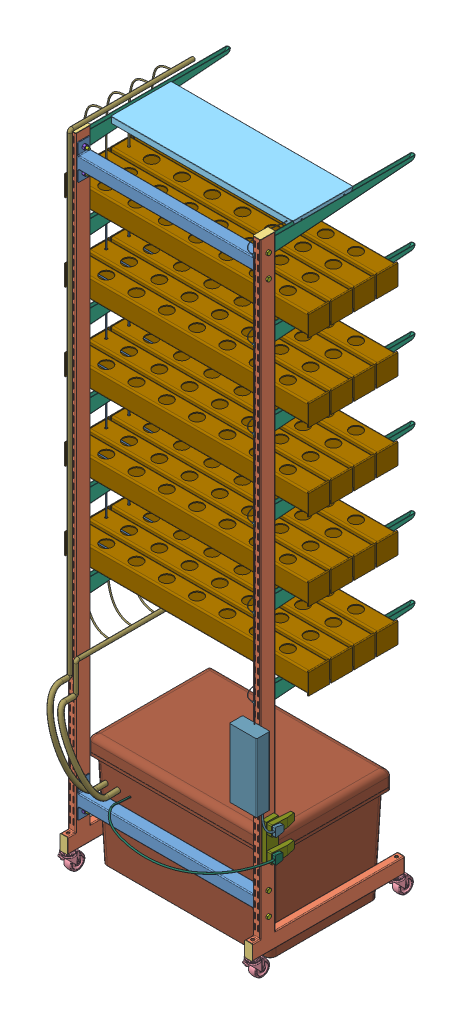
SolidWorks assembly C-L-600, configuration Default. Lengths in mm.
Overall size (806 2127.7 608.88).
90 component instances, 16 part files, 242 mates.
Components (placement in the parent):
- TB-600-1: TB-600 [Default] at (0 2029.5 0) size (585 115 40)
- TB-600-2: TB-600 [Default] at (0 205.5 0) size (585 115 40)
- TSU-F-L-P-1: TSU-F-L-P [Default] at (305 113.5 -25) size (25 2050 500)
- TSU-F-L-P-2: TSU-F-L-P [Default] at (-305 113.5 -25) size (25 2050 500)
- TSU-CAP-1: TSU-CAP [Default] at (-305.1 113.6 -39.9) x (-1 0 0) z (0 0 -1) size (25.2 50.2 6.5)
- TSU-CAP-2: TSU-CAP [Default] at (304.9 113.6 -39.9) x (-1 0 0) z (0 0 -1) size (25.2 50.2 6.5)
- TSU-CAP-3: TSU-CAP [Default] at (305.1 1703.4 -25.1) x (1 0 0) z (0 1 0) size (25.2 50.2 6.5)
- TSU-CAP-4: TSU-CAP [Default] at (304.9 113.6 -360.1) size (25.2 50.2 6.5)
- TSU-CAP-5: TSU-CAP [Default] at (-304.9 1703.4 -25.1) x (1 0 0) z (0 1 0) size (25.2 50.2 6.5)
- TSU-CAP-6: TSU-CAP [Default] at (-304.9 113.6 -360.1) size (25.2 50.2 6.5)
- 2834T320_THREADED-STEM SWIVEL CASTER-1: 2834T320_THREADED-STEM SWIVEL CASTER [2834T32] at (305 82.55 -437.5) x (0 0 -1) z (1 0 0) size (67.73 101.87 56.07)
- 2834T320_THREADED-STEM SWIVEL CASTER-2: 2834T320_THREADED-STEM SWIVEL CASTER [2834T32] at (-305 82.55 37.5) x (0 0 -1) z (1 0 0) size (67.73 101.87 56.07)
- 2834T320_THREADED-STEM SWIVEL CASTER-3: 2834T320_THREADED-STEM SWIVEL CASTER [2834T32] at (305 82.55 37.5) x (0 0 -1) z (1 0 0) size (67.73 101.87 56.07)
- 2834T320_THREADED-STEM SWIVEL CASTER-4: 2834T320_THREADED-STEM SWIVEL CASTER [2834T32] at (-305 82.55 -437.5) x (0 0 -1) z (1 0 0) size (67.73 101.87 56.07)
- TSS-600-1: TSS-600 [Default] at (0 818 -198.7822) size (607 37.13 331.17)
- TSUB-1: TSUB [Default] at (305 766.5 -25) x (-1 0 0) z (0 0 -1) size (14.07 50.86 484.03)
- TSUB-2: TSUB [Default] at (-305 766.5 -25) x (-1 0 0) z (0 0 -1) size (14.07 50.86 484.03)
- TSUB-3: TSUB [Default] at (-305 1022.5 -25) x (-1 0 0) z (0 0 -1) size (14.07 50.86 484.03)
- TSUB-4: TSUB [Default] at (305 1022.5 -25) x (-1 0 0) z (0 0 -1) size (14.07 50.86 484.03)
- TSS-600-2: TSS-600 [Default] at (0 1074 -198.7822) size (607 37.13 331.17)
- TSUB-5: TSUB [Default] at (-305 1534.5 -25) x (-1 0 0) z (0 0 -1) size (14.07 50.86 484.03)
- TSUB-6: TSUB [Default] at (305 1534.5 -25) x (-1 0 0) z (0 0 -1) size (14.07 50.86 484.03)
- TSS-600-3: TSS-600 [Default] at (0 1586 -198.7822) size (607 37.13 331.17)
- TSUB-7: TSUB [Default] at (-305 2046.5 -25) x (-1 0 0) z (0 0 -1) size (14.07 50.86 484.03)
- TSUB-8: TSUB [Default] at (305 2046.5 -25) x (-1 0 0) z (0 0 -1) size (14.07 50.86 484.03)
- TSS-600-4: TSS-600 [Default] at (0 2098 -198.7822) size (607 37.13 331.17)
- TSUB-9: TSUB [Default] at (-305 1278.5 -25) x (-1 0 0) z (0 0 -1) size (14.07 50.86 484.03)
- TSUB-10: TSUB [Default] at (305 1278.5 -25) x (-1 0 0) z (0 0 -1) size (14.07 50.86 484.03)
- TSS-600-5: TSS-600 [Default] at (0 1330 -198.7822) size (607 37.13 331.17)
- TSUB-11: TSUB [Default] at (-305 1790.5 -25) x (-1 0 0) z (0 0 -1) size (14.07 50.86 484.03)
- TSUB-12: TSUB [Default] at (305 1790.5 -25) x (-1 0 0) z (0 0 -1) size (14.07 50.86 484.03)
- TSS-600-6: TSS-600 [Default] at (0 1842 -198.7822) size (607 37.13 331.17)
- hex bolt gradeab2_bsi-10: hex bolt gradeab2_bsi [BS EN 28765 - M8x1 x 45 x 22-N] at (322.8 2067 0) x (-1 0 0) z (0 -0.924225 -0.381849) size (50.3 15.01 13)
- hex bolt gradeab2_bsi-11: hex bolt gradeab2_bsi [BS EN 28765 - M8x1 x 45 x 22-N] at (322.8 1992 0) x (-1 0 0) z (0 -0.999974 0.007224) size (50.3 15.01 13)
- hex bolt gradeab2_bsi-12: hex bolt gradeab2_bsi [BS EN 28765 - M8x1 x 45 x 22-N] at (-322.8 2067 0) size (50.3 15.01 13)
- hex bolt gradeab2_bsi-13: hex bolt gradeab2_bsi [BS EN 28765 - M8x1 x 45 x 22-N] at (-322.8 1992 0) size (50.3 15.01 13)
- hex bolt gradeab2_bsi-14: hex bolt gradeab2_bsi [BS EN 28765 - M8x1 x 45 x 22-N] at (-322.8 168 0) size (50.3 15.01 13)
- hex bolt gradeab2_bsi-15: hex bolt gradeab2_bsi [BS EN 28765 - M8x1 x 45 x 22-N] at (-322.8 243 0) size (50.3 15.01 13)
- hex bolt gradeab2_bsi-16: hex bolt gradeab2_bsi [BS EN 28765 - M8x1 x 45 x 22-N] at (322.8 168 0) x (-1 0 0) z (0 0.924225 0.381849) size (50.3 15.01 13)
- hex bolt gradeab2_bsi-17: hex bolt gradeab2_bsi [BS EN 28765 - M8x1 x 45 x 22-N] at (322.8 243 0) x (-1 0 0) z (0 -0.924225 -0.381849) size (50.3 15.01 13)
- hex nut gradec_bsi-1: hex nut gradec_bsi [BS EN 24034 - M8 - N] at (281.6 2067 0) x (0 0 1) z (-1 0 0) size (13 15.01 7.9)
- hex nut gradec_bsi-2: hex nut gradec_bsi [BS EN 24034 - M8 - N] at (281.6 1992 0) x (0 0 1) z (-1 0 0) size (13 15.01 7.9)
- hex nut gradec_bsi-3: hex nut gradec_bsi [BS EN 24034 - M8 - N] at (-281.6 2067 0) x (0 0 -1) z (1 0 0) size (13 15.01 7.9)
- hex nut gradec_bsi-4: hex nut gradec_bsi [BS EN 24034 - M8 - N] at (-281.6 1992 0) x (0 0.383049 0.923728) z (1 0 0) size (13 15.01 7.9)
- hex nut gradec_bsi-5: hex nut gradec_bsi [BS EN 24034 - M8 - N] at (-281.6 243 0) x (0 0 -1) z (1 0 0) size (13 15.01 7.9)
- hex nut gradec_bsi-6: hex nut gradec_bsi [BS EN 24034 - M8 - N] at (281.6 243 0) x (0 0 1) z (-1 0 0) size (13 15.01 7.9)
- hex nut gradec_bsi-7: hex nut gradec_bsi [BS EN 24034 - M8 - N] at (281.6 168 0) x (0 0 1) z (-1 0 0) size (13 15.01 7.9)
- hex nut gradec_bsi-8: hex nut gradec_bsi [BS EN 24034 - M8 - N] at (-281.6 168 0) x (0 0 -1) z (1 0 0) size (13 15.01 7.9)
- GB-600-b-1: GB-600-b [Default] at (0 1106.5 -233.7344) size (806 70 70)
- GB-600-p-1: GB-600-p [Default] at (0 1106.5 -233.7344) size (92 218.31 4)
- GB-600-p-2: GB-600-p [Default] at (0 1106.5 -308.7344) size (92 218.31 4)
- GB-600-b-2: GB-600-b [Default] at (0 1106.5 -308.7344) size (806 70 70)
- GB-600-p-3: GB-600-p [Default] at (0 1106.5 -83.7344) size (92 218.31 4)
- GB-600-b-3: GB-600-b [Default] at (0 1106.5 -83.7344) size (806 70 70)
- GB-600-p-4: GB-600-p [Default] at (0 1106.5 -158.7344) size (92 218.31 4)
- GB-600-b-4: GB-600-b [Default] at (0 1106.5 -158.7344) size (806 70 70)
- GB-600-b-5: GB-600-b [Default] at (0 850.5 -83.7344) size (806 70 70)
- GB-600-b-6: GB-600-b [Default] at (0 850.5 -158.7344) size (806 70 70)
- GB-600-b-7: GB-600-b [Default] at (0 850.5 -233.7344) size (806 70 70)
- GB-600-b-8: GB-600-b [Default] at (0 850.5 -308.7344) size (806 70 70)
- GB-600-b-9: GB-600-b [Default] at (0 1618.5 -83.7344) size (806 70 70)
- GB-600-b-10: GB-600-b [Default] at (0 1618.5 -158.7344) size (806 70 70)
- GB-600-b-11: GB-600-b [Default] at (0 1618.5 -233.7344) size (806 70 70)
- GB-600-b-12: GB-600-b [Default] at (0 1618.5 -308.7344) size (806 70 70)
- GB-600-p-5: GB-600-p [Default] at (0 1618.5 -83.7344) size (92 218.31 4)
- GB-600-p-6: GB-600-p [Default] at (0 1618.5 -158.7344) size (92 218.31 4)
- GB-600-p-7: GB-600-p [Default] at (0 1618.5 -233.7344) size (92 218.31 4)
- GB-600-p-8: GB-600-p [Default] at (0 1618.5 -308.7344) size (92 218.31 4)
- GB-600-p-9: GB-600-p [Default] at (0 1362.5 -308.7344) size (92 218.31 4)
- GB-600-p-10: GB-600-p [Default] at (0 1362.5 -233.7344) size (92 218.31 4)
- GB-600-p-11: GB-600-p [Default] at (0 1362.5 -158.7344) size (92 218.31 4)
- GB-600-p-12: GB-600-p [Default] at (0 1362.5 -83.7344) size (92 218.31 4)
- GB-600-b-13: GB-600-b [Default] at (0 1362.5 -308.7344) size (806 70 70)
- GB-600-b-14: GB-600-b [Default] at (0 1362.5 -233.7344) size (806 70 70)
- GB-600-b-15: GB-600-b [Default] at (0 1362.5 -158.7344) size (806 70 70)
- GB-600-b-16: GB-600-b [Default] at (0 1362.5 -83.7344) size (806 70 70)
- GB-600-p-13: GB-600-p [Default] at (0 1874.5 -308.7344) size (92 218.31 4)
- GB-600-p-14: GB-600-p [Default] at (0 1874.5 -233.7344) size (92 218.31 4)
- GB-600-p-15: GB-600-p [Default] at (0 1874.5 -158.7344) size (92 218.31 4)
- GB-600-p-16: GB-600-p [Default] at (0 1874.5 -83.7344) size (92 218.31 4)
- GB-600-b-17: GB-600-b [Default] at (0 1874.5 -83.7344) size (806 70 70)
- GB-600-b-18: GB-600-b [Default] at (0 1874.5 -158.7344) size (806 70 70)
- GB-600-b-19: GB-600-b [Default] at (0 1874.5 -233.7344) size (806 70 70)
- GB-600-b-20: GB-600-b [Default] at (0 1874.5 -308.7344) size (806 70 70)
- WT-1: WT [Default] at (0 320 -225) size (600 370 400)
- Plumbing-1: Plumbing [Default] at (-305 113.5 25) size (241.4 2067.5 489.85)
- Wire-1: Wire [Default] at (0 2060.8692 -198.7822) x (-1 0 0) z (0 -1 0) size (2 2 1357)
- CCD-1: CCD [Default] at (305 113.5 -25) x (0 0 -1) z (1 0 0) size (82.56 307.09 97.63)
- Pump-1: Pump [Default] at (0 5 -225) x (1 0 0) z (0 1 0) size (624.24 196.22 364.08)
- Power Bar-1: Power Bar [Default] at (317.5 113.5 -25) x (0 0 -1) z (1 0 0) size (82.62 120 30)
Mates (geometry in assembly coordinates):
- Coincident5: coincident aligned: plane of TB-600-2 through (0 205.5 0) normal (1 0 0)
- Coincident6: coincident aligned: plane of TB-600-2 through (0 205.5 0) normal (0 0 1)
- Tangent1: tangent anti-aligned: torus of 2834T320_THREADED-STEM SWIVEL CASTER-1
- Concentric5: concentric anti-aligned: cylinder of TSU-F-L-P-1 through (305 113.5 -437.5) axis (0 -1 0) radius 5.1; cylinder of 2834T320_THREADED-STEM SWIVEL CASTER-1 through (305 101.6 -437.5) axis (0 1 0) radius 4.7625
- Coincident7: coincident anti-aligned: plane of TB-600-2 through (292.5 205.5 0) normal (1 0 0); plane of TSU-F-L-P-1 through (292.5 2113.5 -22) normal (-1 0 0)
- Concentric6: concentric anti-aligned: cylinder of TB-600-2 through (292.5 243 0) axis (-1 0 0) radius 4.5; cylinder of TSU-F-L-P-1 through (290.9 243 0) axis (1 0 0) radius 4.5
- Coincident8: coincident anti-aligned: plane of TSU-F-L-P-1 through (305 63.5 -450) normal (0 -1 0); plane of 2834T320_THREADED-STEM SWIVEL CASTER-1 through (305 63.5 -421.3957) normal (0 1 0)
- Concentric7: concentric anti-aligned: cylinder of TB-600-1 through (292.5 2067 0) axis (-1 0 0) radius 4.5; cylinder of TSU-F-L-P-1 through (292.5 2067 0) axis (1 0 0) radius 4.5
- Coincident9: coincident anti-aligned: plane of TB-600-1 through (292.5 2029.5 0) normal (1 0 0); plane of TSU-F-L-P-1 through (292.5 2113.5 -22) normal (-1 0 0)
- Concentric8: concentric aligned: cylinder of TB-600-2 through (-292.5 168 0) axis (1 0 0) radius 4.5; cylinder of TSU-F-L-P-2 through (-319.1 168 0) axis (1 0 0) radius 4.5
- Coincident10: coincident anti-aligned: plane of TB-600-2 through (-292.5 205.5 0) normal (-1 0 0); plane of TSU-F-L-P-2 through (-292.5 2113.5 -22) normal (1 0 0)
- Concentric9: concentric anti-aligned: cylinder of TSU-F-L-P-2 through (-305 113.5 -437.5) axis (0 -1 0) radius 5.1; cylinder of 2834T320_THREADED-STEM SWIVEL CASTER-4 through (-305 101.6 -437.5) axis (0 1 0) radius 4.7625
- Concentric10: concentric aligned: cylinder of TB-600-1 through (-292.5 1992 0) axis (1 0 0) radius 4.5; cylinder of TSU-F-L-P-2 through (-317.5 1992 0) axis (1 0 0) radius 4.5
- Concentric11: concentric aligned: cylinder of TB-600-1 through (-292.5 2067 0) axis (1 0 0) radius 4.5; cylinder of TSU-F-L-P-2 through (-317.5 2067 0) axis (1 0 0) radius 4.5
- Parallel4: parallel aligned: plane of TSU-F-L-P-1 through (317.5 2113.5 -22) normal (1 0 0); plane of 2834T320_THREADED-STEM SWIVEL CASTER-1 through (316.9062 47.2916 -458.1375) normal (1 0 0)
- Coincident16: coincident anti-aligned: plane of TSU-F-L-P-2 through (-305 63.5 -450) normal (0 -1 0); plane of 2834T320_THREADED-STEM SWIVEL CASTER-4 through (-305 63.5 -421.3957) normal (0 1 0)
- Concentric12: concentric anti-aligned: cylinder of TSU-F-L-P-1 through (305 113.5 37.5) axis (0 -1 0) radius 5.1; cylinder of 2834T320_THREADED-STEM SWIVEL CASTER-3 through (305 101.6 37.5) axis (0 1 0) radius 4.7625
- Coincident17: coincident anti-aligned: plane of TSU-F-L-P-1 through (305 63.5 -450) normal (0 -1 0); plane of 2834T320_THREADED-STEM SWIVEL CASTER-3 through (305 63.5 53.6043) normal (0 1 0)
- Coincident18: coincident aligned: plane of 2834T320_THREADED-STEM SWIVEL CASTER-1 through (316.9062 47.2916 -458.1375) normal (1 0 0); plane of 2834T320_THREADED-STEM SWIVEL CASTER-3 through (316.9062 47.2916 16.8625) normal (1 0 0)
- Concentric13: concentric anti-aligned: cylinder of TSU-F-L-P-2 through (-305 113.5 37.5) axis (0 -1 0) radius 5.1; cylinder of 2834T320_THREADED-STEM SWIVEL CASTER-2 through (-305 101.6 37.5) axis (0 1 0) radius 4.7625
- Coincident19: coincident anti-aligned: plane of TSU-F-L-P-2 through (-305 63.5 -450) normal (0 -1 0); plane of 2834T320_THREADED-STEM SWIVEL CASTER-2 through (-305 63.5 53.6043) normal (0 1 0)
- Parallel6: parallel aligned: plane of TSU-F-L-P-2 through (-317.5 2113.5 -22) normal (-1 0 0); plane of 2834T320_THREADED-STEM SWIVEL CASTER-2 through (-316.9062 47.2916 16.8625) normal (-1 0 0)
- Coincident21: coincident anti-aligned: plane of TSU-F-L-P-1 through (294 2113.5 0) normal (1 0 0); plane of TSU-CAP-4 through (294 113.6 45) normal (-1 0 0)
- Coincident22: coincident anti-aligned: plane of TSU-F-L-P-1 through (314.5 112 -450) normal (0 -1 0); plane of TSU-CAP-4 through (304.9 112 45) normal (0 1 0)
- Coincident23: coincident anti-aligned: plane of TSU-F-L-P-1 through (314.5 110.5 50) normal (0 0 1); plane of TSU-CAP-4 through (304.9 113.6 50) normal (0 0 -1)
- Coincident24: coincident anti-aligned: plane of TSU-F-L-P-2 through (-294 2113.5 0) normal (-1 0 0); plane of TSU-CAP-6 through (-294 113.6 45) normal (1 0 0)
- Coincident25: coincident anti-aligned: plane of TSU-F-L-P-2 through (-295.5 112 -450) normal (0 -1 0); plane of TSU-CAP-6 through (-304.9 112 45) normal (0 1 0)
- Coincident26: coincident anti-aligned: plane of TSU-F-L-P-2 through (-295.5 110.5 50) normal (0 0 1); plane of TSU-CAP-6 through (-304.9 113.6 50) normal (0 0 -1)
- Coincident27: coincident anti-aligned: plane of TSU-F-L-P-1 through (294 2113.5 0) normal (1 0 0); plane of TSU-CAP-2 through (294 113.6 -445) normal (-1 0 0)
- Coincident28: coincident anti-aligned: plane of TSU-F-L-P-1 through (314.5 112 -450) normal (0 -1 0); plane of TSU-CAP-2 through (304.9 112 -445) normal (0 1 0)
- Coincident29: coincident anti-aligned: plane of TSU-F-L-P-1 through (314.5 110.5 -450) normal (0 0 -1); plane of TSU-CAP-2 through (304.9 113.6 -450) normal (0 0 1)
- Coincident30: coincident anti-aligned: plane of TSU-F-L-P-2 through (-316 2113.5 0) normal (1 0 0); plane of TSU-CAP-1 through (-316 113.6 -445) normal (-1 0 0)
- Coincident31: coincident anti-aligned: plane of TSU-F-L-P-2 through (-295.5 112 -450) normal (0 -1 0); plane of TSU-CAP-1 through (-305.1 112 -445) normal (0 1 0)
- Coincident32: coincident anti-aligned: plane of TSU-F-L-P-2 through (-295.5 110.5 -450) normal (0 0 -1); plane of TSU-CAP-1 through (-305.1 113.6 -450) normal (0 0 1)
- Coincident33: coincident anti-aligned: plane of TSU-F-L-P-1 through (316 2113.5 0) normal (-1 0 0); plane of TSU-CAP-3 through (316 2108.5 -25.1) normal (1 0 0)
- Coincident34: coincident anti-aligned: plane of TSU-F-L-P-1 through (314.5 2113.5 -23.5) normal (0 0 1); plane of TSU-CAP-3 through (305.1 2108.5 -23.5) normal (0 0 -1)
- Coincident35: coincident anti-aligned: plane of TSU-F-L-P-1 through (314.5 2113.5 -22) normal (0 1 0); plane of TSU-CAP-3 through (305.1 2113.5 -25.1) normal (0 -1 0)
- Coincident36: coincident anti-aligned: plane of TSU-F-L-P-2 through (-294 2113.5 0) normal (-1 0 0); plane of TSU-CAP-5 through (-294 2108.5 -25.1) normal (1 0 0)
- Coincident37: coincident anti-aligned: plane of TSU-F-L-P-2 through (-295.5 2113.5 -23.5) normal (0 0 1); plane of TSU-CAP-5 through (-304.9 2108.5 -23.5) normal (0 0 -1)
- Coincident38: coincident anti-aligned: plane of TSU-F-L-P-2 through (-295.5 2113.5 -22) normal (0 1 0); plane of TSU-CAP-5 through (-304.9 2113.5 -25.1) normal (0 -1 0)
- Parallel7: parallel aligned: plane of TSU-F-L-P-2 through (-292.5 2113.5 -22) normal (1 0 0); plane of 2834T320_THREADED-STEM SWIVEL CASTER-4 through (-293.0938 47.2916 -458.1375) normal (1 0 0)
- Coincident41: coincident anti-aligned: plane of TSU-F-L-P-1 through (298 273.5 0.001) normal (1 0 0); plane of TSUB-1 through (298 766.5 -25) normal (-1 0 0)
- Coincident42: coincident anti-aligned: plane of TSU-F-L-P-1 through (305 2113.5 -25) normal (0 0 -1); plane of TSUB-1 through (312 766.5 -25) normal (0 0 1)
- Parallel8: parallel: line of TSU-F-L-P-1 through (309 342 -23.5) axis (0 0 -1); plane of TSUB-1 through (298 816.5 -25) normal (0 1 0)
- Coincident44: coincident anti-aligned: plane of TSS-600-1 through (299.5 798 -198.7822) normal (-1 0 0); plane of TSUB-1 through (299.5 766.5 -25) normal (1 0 0)
- Coincident45: coincident anti-aligned: plane of TSS-600-1 through (301 816.5 -100.2822) normal (0 -1 0); plane of TSUB-1 through (298 816.5 -25) normal (0 1 0)
- Coincident46: coincident anti-aligned: plane of TSU-F-L-P-2 through (-312 369.5 0.001) normal (1 0 0); plane of TSUB-2 through (-312 766.5 -25) normal (-1 0 0)
- Coincident47: coincident anti-aligned: plane of TSU-F-L-P-2 through (-305 2113.5 -25) normal (0 0 -1); plane of TSUB-2 through (-312 766.5 -25) normal (0 0 1)
- Coincident48: coincident anti-aligned: plane of TSS-600-1 through (301 816.5 -100.2822) normal (0 -1 0); plane of TSUB-2 through (-312 816.5 -25) normal (0 1 0)
- Coincident49: coincident anti-aligned: plane of TSU-F-L-P-1 through (312 1041.5 0.001) normal (-1 0 0); plane of TSUB-4 through (312 1022.5 -25) normal (1 0 0)
- Coincident50: coincident anti-aligned: plane of TSU-F-L-P-1 through (305 2113.5 -25) normal (0 0 -1); plane of TSUB-4 through (312 1022.5 -25) normal (0 0 1)
- Coincident51: coincident anti-aligned: plane of TSU-F-L-P-2 through (-298 1073.5 0.001) normal (-1 0 0); plane of TSUB-3 through (-298 1022.5 -25) normal (1 0 0)
- Coincident52: coincident anti-aligned: plane of TSU-F-L-P-2 through (-305 2113.5 -25) normal (0 0 -1); plane of TSUB-3 through (-312 1022.5 -25) normal (0 0 1)
- Coincident53: coincident anti-aligned: plane of TSUB-4 through (298 1072.5 -25) normal (0 1 0); plane of TSS-600-2 through (301 1072.5 -100.2822) normal (0 -1 0)
- Coincident54: coincident anti-aligned: plane of TSUB-3 through (-312 1072.5 -25) normal (0 1 0); plane of TSS-600-2 through (301 1072.5 -100.2822) normal (0 -1 0)
- Coincident55: coincident anti-aligned: plane of TSUB-4 through (299.5 1022.5 -25) normal (1 0 0); plane of TSS-600-2 through (299.5 1054 -198.7822) normal (-1 0 0)
- Coincident56: coincident anti-aligned: plane of TSUB-6 through (299.5 1534.5 -25) normal (1 0 0); plane of TSS-600-3 through (299.5 1566 -198.7822) normal (-1 0 0)
- Coincident57: coincident anti-aligned: plane of TSUB-6 through (298 1584.5 -25) normal (0 1 0); plane of TSS-600-3 through (301 1584.5 -100.2822) normal (0 -1 0)
- Coincident58: coincident anti-aligned: plane of TSUB-5 through (-312 1584.5 -25) normal (0 1 0); plane of TSS-600-3 through (301 1584.5 -100.2822) normal (0 -1 0)
- Coincident59: coincident anti-aligned: plane of TSUB-8 through (299.5 2046.5 -25) normal (1 0 0); plane of TSS-600-4 through (299.5 2078 -198.7822) normal (-1 0 0)
- Coincident60: coincident anti-aligned: plane of TSUB-8 through (298 2096.5 -25) normal (0 1 0); plane of TSS-600-4 through (301 2096.5 -100.2822) normal (0 -1 0)
- Coincident61: coincident anti-aligned: plane of TSUB-7 through (-312 2096.5 -25) normal (0 1 0); plane of TSS-600-4 through (301 2096.5 -100.2822) normal (0 -1 0)
- Coincident62: coincident anti-aligned: plane of TSUB-10 through (299.5 1278.5 -25) normal (1 0 0); plane of TSS-600-5 through (299.5 1310 -198.7822) normal (-1 0 0)
- Coincident63: coincident anti-aligned: plane of TSUB-10 through (298 1328.5 -25) normal (0 1 0); plane of TSS-600-5 through (301 1328.5 -100.2822) normal (0 -1 0)
- Coincident64: coincident anti-aligned: plane of TSUB-9 through (-312 1328.5 -25) normal (0 1 0); plane of TSS-600-5 through (301 1328.5 -100.2822) normal (0 -1 0)
- Coincident65: coincident anti-aligned: plane of TSUB-12 through (299.5 1790.5 -25) normal (1 0 0); plane of TSS-600-6 through (299.5 1822 -198.7822) normal (-1 0 0)
- Coincident66: coincident anti-aligned: plane of TSUB-12 through (298 1840.5 -25) normal (0 1 0); plane of TSS-600-6 through (301 1840.5 -100.2822) normal (0 -1 0)
- Coincident67: coincident anti-aligned: plane of TSUB-11 through (-312 1840.5 -25) normal (0 1 0); plane of TSS-600-6 through (301 1840.5 -100.2822) normal (0 -1 0)
- Coincident70: coincident anti-aligned: plane of TSU-F-L-P-1 through (305 2113.5 -25) normal (0 0 -1); plane of TSUB-10 through (298 1278.5 -25) normal (0 0 1)
- Coincident71: coincident anti-aligned: plane of TSU-F-L-P-2 through (-305 2113.5 -25) normal (0 0 -1); plane of TSUB-9 through (-312 1278.5 -25) normal (0 0 1)
- Coincident72: coincident aligned: plane of TSUB-3 through (-298 1022.5 -25) normal (1 0 0); plane of TSUB-9 through (-298 1278.5 -25) normal (1 0 0)
- Coincident73: coincident aligned: plane of TSUB-4 through (298 1022.5 -25) normal (-1 0 0); plane of TSUB-10 through (298 1278.5 -25) normal (-1 0 0)
- Coincident74: coincident anti-aligned: plane of TSU-F-L-P-1 through (305 2113.5 -25) normal (0 0 -1); plane of TSUB-6 through (298 1534.5 -25) normal (0 0 1)
- Coincident75: coincident anti-aligned: plane of TSU-F-L-P-2 through (-305 2113.5 -25) normal (0 0 -1); plane of TSUB-5 through (-312 1534.5 -25) normal (0 0 1)
- Coincident76: coincident aligned: plane of TSUB-5 through (-298 1534.5 -25) normal (1 0 0); plane of TSUB-9 through (-298 1278.5 -25) normal (1 0 0)
- Coincident78: coincident aligned: plane of TSUB-6 through (312 1534.5 -25) normal (1 0 0); plane of TSUB-12 through (312 1790.5 -25) normal (1 0 0)
- Coincident79: coincident aligned: plane of TSUB-6 through (298 1534.5 -25) normal (-1 0 0); plane of TSUB-10 through (298 1278.5 -25) normal (-1 0 0)
- Coincident80: coincident anti-aligned: plane of TSU-F-L-P-1 through (305 2113.5 -25) normal (0 0 -1); plane of TSUB-12 through (298 1790.5 -25) normal (0 0 1)
- Coincident81: coincident anti-aligned: plane of TSU-F-L-P-2 through (-312 1873.5 0.001) normal (1 0 0); plane of TSUB-11 through (-312 1790.5 -25) normal (-1 0 0)
- Coincident82: coincident anti-aligned: plane of TSU-F-L-P-2 through (-305 2113.5 -25) normal (0 0 -1); plane of TSUB-11 through (-312 1790.5 -25) normal (0 0 1)
- Coincident83: coincident anti-aligned: plane of TSU-F-L-P-2 through (-312 1969.5 0.001) normal (1 0 0); plane of TSUB-7 through (-312 2046.5 -25) normal (-1 0 0)
- Coincident84: coincident anti-aligned: plane of TSU-F-L-P-2 through (-305 2113.5 -25) normal (0 0 -1); plane of TSUB-7 through (-312 2046.5 -25) normal (0 0 1)
- Coincident85: coincident anti-aligned: plane of TSU-F-L-P-1 through (298 2001.5 0.001) normal (1 0 0); plane of TSUB-8 through (298 2046.5 -25) normal (-1 0 0)
- Coincident86: coincident anti-aligned: plane of TSU-F-L-P-1 through (305 2113.5 -25) normal (0 0 -1); plane of TSUB-8 through (298 2046.5 -25) normal (0 0 1)
- Coincident89: coincident: line of TSU-F-L-P-1 through (309 2070 -23.5) axis (0 0 -1); plane of TSUB-8 through (333.2603 2070 -25) normal (0 1 0)
- Coincident90: coincident aligned: plane of TSS-600-4 through (301 2098 -298.7822) normal (0 0 -1); plane of TSS-600-6 through (301 1842 -298.7822) normal (0 0 -1)
- Coincident91: coincident aligned: plane of TSS-600-3 through (301 1586 -298.7822) normal (0 0 -1); plane of TSS-600-6 through (301 1842 -298.7822) normal (0 0 -1)
- Coincident93: coincident aligned: plane of TSS-600-3 through (301 1586 -298.7822) normal (0 0 -1); plane of TSS-600-5 through (301 1330 -298.7822) normal (0 0 -1)
- Coincident94: coincident aligned: plane of TSS-600-2 through (301 1074 -298.7822) normal (0 0 -1); plane of TSS-600-5 through (301 1330 -298.7822) normal (0 0 -1)
- Coincident95: coincident aligned: plane of TSS-600-1 through (301 818 -298.7822) normal (0 0 -1); plane of TSS-600-2 through (301 1074 -298.7822) normal (0 0 -1)
- Coincident153: coincident: line of TSU-F-L-P-1 through (312 1814 -23.5) axis (0 0 -1); plane of TSUB-12 through (333.2603 1814 -25) normal (0 1 0)
- Coincident155: coincident: line of TSU-F-L-P-1 through (312 1558 -23.5) axis (0 0 -1); plane of TSUB-6 through (333.2603 1558 -25) normal (0 1 0)
- Coincident157: coincident: line of TSU-F-L-P-1 through (312 1302 -23.5) axis (0 0 -1); plane of TSUB-10 through (333.2603 1302 -25) normal (0 1 0)
- Coincident159: coincident: line of TSU-F-L-P-1 through (312 1046 -23.5) axis (0 0 -1); plane of TSUB-4 through (333.2603 1046 -25) normal (0 1 0)
- Coincident167: coincident: line of TSU-F-L-P-1 through (312 790 -23.5) axis (0 0 -1); plane of TSUB-1 through (333.2603 790 -25) normal (0 1 0)
- Concentric15: concentric aligned: cylinder of TSU-F-L-P-1 through (292.5 2067 0) axis (1 0 0) radius 4.5; cylinder of hex bolt gradeab2_bsi-10 through (322.8 2067 0) axis (1 0 0) radius 4
- Coincident181: coincident anti-aligned: plane of TSU-F-L-P-1 through (317.5 2113.5 -22) normal (1 0 0); plane of hex bolt gradeab2_bsi-10 through (317.5 2069.866 -6.9368) normal (-1 0 0)
- Concentric16: concentric aligned: cylinder of TSU-F-L-P-1 through (292.5 1992 0) axis (1 0 0) radius 4.5; cylinder of hex bolt gradeab2_bsi-11 through (322.8 1992 0) axis (1 0 0) radius 4
- Coincident182: coincident anti-aligned: plane of TSU-F-L-P-1 through (317.5 2113.5 -22) normal (1 0 0); plane of hex bolt gradeab2_bsi-11 through (317.5 1991.9458 -7.5054) normal (-1 0 0)
- Concentric17: concentric anti-aligned: cylinder of TB-600-1 through (-292.5 2067 0) axis (1 0 0) radius 4.5; cylinder of hex bolt gradeab2_bsi-12 through (-322.8 2067 0) axis (-1 0 0) radius 4
- Coincident183: coincident anti-aligned: plane of TSU-F-L-P-2 through (-317.5 2113.5 -22) normal (-1 0 0); plane of hex bolt gradeab2_bsi-12 through (-317.5 2074.5056 0) normal (1 0 0)
- Concentric18: concentric anti-aligned: cylinder of TB-600-1 through (-292.5 1992 0) axis (1 0 0) radius 4.5; cylinder of hex bolt gradeab2_bsi-13 through (-322.8 1992 0) axis (-1 0 0) radius 4
- Coincident184: coincident anti-aligned: plane of TSU-F-L-P-2 through (-317.5 2113.5 -22) normal (-1 0 0); plane of hex bolt gradeab2_bsi-13 through (-317.5 1999.5056 0) normal (1 0 0)
- Concentric19: concentric anti-aligned: cylinder of TB-600-2 through (-292.5 243 0) axis (1 0 0) radius 4.5; cylinder of hex bolt gradeab2_bsi-15 through (-322.8 243 0) axis (-1 0 0) radius 4
- Coincident185: coincident anti-aligned: plane of TSU-F-L-P-2 through (-317.5 2113.5 -22) normal (-1 0 0); plane of hex bolt gradeab2_bsi-15 through (-317.5 250.5056 0) normal (1 0 0)
- Concentric20: concentric anti-aligned: cylinder of TB-600-2 through (-292.5 168 0) axis (1 0 0) radius 4.5; cylinder of hex bolt gradeab2_bsi-14 through (-322.8 168 0) axis (-1 0 0) radius 4
- Coincident186: coincident anti-aligned: plane of TSU-F-L-P-2 through (-317.5 2113.5 -22) normal (-1 0 0); plane of hex bolt gradeab2_bsi-14 through (-317.5 175.5056 0) normal (1 0 0)
- Concentric21: concentric anti-aligned: cylinder of TB-600-2 through (292.5 243 0) axis (-1 0 0) radius 4.5; cylinder of hex bolt gradeab2_bsi-17 through (322.8 243 0) axis (1 0 0) radius 4
- Coincident187: coincident anti-aligned: plane of TSU-F-L-P-1 through (317.5 2113.5 -22) normal (1 0 0); plane of hex bolt gradeab2_bsi-17 through (317.5 245.866 -6.9368) normal (-1 0 0)
- Concentric22: concentric aligned: cylinder of TSU-F-L-P-1 through (290.9 168 0) axis (1 0 0) radius 4.5; cylinder of hex bolt gradeab2_bsi-16 through (322.8 168 0) axis (1 0 0) radius 4
- Coincident188: coincident anti-aligned: plane of TSU-F-L-P-1 through (317.5 2113.5 -22) normal (1 0 0); plane of hex bolt gradeab2_bsi-16 through (317.5 165.134 6.9368) normal (-1 0 0)
- Concentric23: concentric anti-aligned: cylinder of hex bolt gradeab2_bsi-10 through (322.8 2067 0) axis (1 0 0) radius 4; cylinder of hex nut gradec_bsi-1 through (289.5 2067 0) axis (-1 0 0) radius 3.4
- Coincident189: coincident anti-aligned: plane of TB-600-1 through (289.5 2029.5 0) normal (-1 0 0); plane of hex nut gradec_bsi-1 through (289.5 2074.5056 0) normal (1 0 0)
- Concentric24: concentric anti-aligned: cylinder of hex bolt gradeab2_bsi-11 through (322.8 1992 0) axis (1 0 0) radius 4; cylinder of hex nut gradec_bsi-2 through (289.5 1992 0) axis (-1 0 0) radius 3.4
- Coincident190: coincident anti-aligned: plane of TB-600-1 through (289.5 2029.5 0) normal (-1 0 0); plane of hex nut gradec_bsi-2 through (289.5 1999.5056 0) normal (1 0 0)
- Concentric25: concentric anti-aligned: cylinder of hex bolt gradeab2_bsi-12 through (-322.8 2067 0) axis (-1 0 0) radius 4; cylinder of hex nut gradec_bsi-3 through (-289.5 2067 0) axis (1 0 0) radius 3.4
- Coincident191: coincident anti-aligned: plane of TB-600-1 through (-289.5 2029.5 0) normal (1 0 0); plane of hex nut gradec_bsi-3 through (-289.5 2074.5056 0) normal (-1 0 0)
- Concentric26: concentric anti-aligned: cylinder of hex bolt gradeab2_bsi-13 through (-322.8 1992 0) axis (-1 0 0) radius 4; cylinder of hex nut gradec_bsi-4 through (-289.5 1992 0) axis (1 0 0) radius 3.4
- Coincident192: coincident anti-aligned: plane of TB-600-1 through (-289.5 2029.5 0) normal (1 0 0); plane of hex nut gradec_bsi-4 through (-289.5 1985.0669 2.875) normal (-1 0 0)
- Concentric27: concentric anti-aligned: cylinder of hex bolt gradeab2_bsi-15 through (-322.8 243 0) axis (-1 0 0) radius 4; cylinder of hex nut gradec_bsi-5 through (-289.5 243 0) axis (1 0 0) radius 3.4
- Coincident193: coincident anti-aligned: plane of TB-600-2 through (-289.5 205.5 0) normal (1 0 0); plane of hex nut gradec_bsi-5 through (-289.5 250.5056 0) normal (-1 0 0)
- Concentric28: concentric anti-aligned: cylinder of hex bolt gradeab2_bsi-14 through (-322.8 168 0) axis (-1 0 0) radius 4; cylinder of hex nut gradec_bsi-8 through (-289.5 168 0) axis (1 0 0) radius 3.4
- Coincident194: coincident anti-aligned: plane of TB-600-2 through (-289.5 205.5 0) normal (1 0 0); plane of hex nut gradec_bsi-8 through (-289.5 175.5056 0) normal (-1 0 0)
- Concentric29: concentric anti-aligned: cylinder of hex bolt gradeab2_bsi-17 through (322.8 243 0) axis (1 0 0) radius 4; cylinder of hex nut gradec_bsi-6 through (289.5 243 0) axis (-1 0 0) radius 3.4
- Concentric30: concentric anti-aligned: cylinder of hex bolt gradeab2_bsi-16 through (322.8 168 0) axis (1 0 0) radius 4; cylinder of hex nut gradec_bsi-7 through (289.5 168 0) axis (-1 0 0) radius 3.4
- Coincident195: coincident anti-aligned: plane of TB-600-2 through (289.5 205.5 0) normal (-1 0 0); plane of hex nut gradec_bsi-6 through (289.5 250.5056 0) normal (1 0 0)
- Coincident196: coincident anti-aligned: plane of TB-600-2 through (289.5 205.5 0) normal (-1 0 0); plane of hex nut gradec_bsi-7 through (289.5 175.5056 0) normal (1 0 0)
- Concentric31: concentric aligned: cylinder of GB-600-b-1 through (-375 1071.5 -233.7344) axis (0 1 0) radius 2; cylinder of GB-600-p-1 through (-375 877 -233.7344) axis (0 1 0) radius 2
- Distance1: distance = 10 mm aligned: plane of GB-600-p-1 through (-375 1087 -233.7344) normal (0 1 0); plane of GB-600-b-1 through (400 1077 -201.2344) normal (0 1 0)
- Parallel10: parallel anti-aligned: plane of TSU-F-L-P-1 through (305 2113.5 -25) normal (0 0 -1); plane of GB-600-b-1 through (400 1074 -201.2344) normal (0 0 1)
- Coincident201: coincident aligned: plane of GB-600-b-1 through (0 1106.5 -233.7344) normal (1 0 0)
- Coincident202: coincident anti-aligned: plane of TSS-600-2 through (301 1074 -98.7822) normal (0 1 0); plane of GB-600-b-1 through (400 1074 -201.2344) normal (0 -1 0)
- Concentric32: concentric aligned: cylinder of GB-600-p-2 through (-375 877 -308.7344) axis (0 1 0) radius 2; cylinder of GB-600-b-2 through (-375 1071.5 -308.7344) axis (0 1 0) radius 2
- Distance2: distance = 10 mm aligned: plane of GB-600-p-2 through (-375 1087 -308.7344) normal (0 1 0); plane of GB-600-b-2 through (400 1077 -276.2344) normal (0 1 0)
- Concentric33: concentric aligned: cylinder of GB-600-p-3 through (-375 877 -83.7344) axis (0 1 0) radius 2; cylinder of GB-600-b-3 through (-375 1071.5 -83.7344) axis (0 1 0) radius 2
- Distance3: distance = 10 mm aligned: plane of GB-600-p-3 through (-375 1087 -83.7344) normal (0 1 0); plane of GB-600-b-3 through (400 1077 -51.2344) normal (0 1 0)
- Concentric34: concentric aligned: cylinder of GB-600-p-4 through (-375 877 -158.7344) axis (0 1 0) radius 2; cylinder of GB-600-b-4 through (-375 1071.5 -158.7344) axis (0 1 0) radius 2
- Distance4: distance = 10 mm aligned: plane of GB-600-p-4 through (-375 1087 -158.7344) normal (0 1 0); plane of GB-600-b-4 through (400 1077 -126.2344) normal (0 1 0)
- Coincident203: coincident anti-aligned: plane of TSS-600-2 through (301 1074 -98.7822) normal (0 1 0); plane of GB-600-b-2 through (400 1074 -276.2344) normal (0 -1 0)
- Coincident204: coincident anti-aligned: plane of TSS-600-2 through (301 1074 -98.7822) normal (0 1 0); plane of GB-600-b-4 through (400 1074 -126.2344) normal (0 -1 0)
- Coincident205: coincident anti-aligned: plane of TSS-600-2 through (301 1074 -98.7822) normal (0 1 0); plane of GB-600-b-3 through (400 1074 -51.2344) normal (0 -1 0)
- Coincident206: coincident aligned: plane of GB-600-b-1 through (403 1106.5 -233.7344) normal (1 0 0); plane of GB-600-b-4 through (403 1106.5 -158.7344) normal (1 0 0)
- Coincident207: coincident aligned: plane of GB-600-b-3 through (403 1106.5 -83.7344) normal (1 0 0); plane of GB-600-b-4 through (403 1106.5 -158.7344) normal (1 0 0)
- Coincident208: coincident aligned: plane of GB-600-b-1 through (403 1106.5 -233.7344) normal (1 0 0); plane of GB-600-b-2 through (403 1106.5 -308.7344) normal (1 0 0)
- Distance5: distance = 10 mm anti-aligned: plane of GB-600-b-4 through (400 1074 -191.2344) normal (0 0 -1); plane of GB-600-b-1 through (400 1074 -201.2344) normal (0 0 1)
- Distance6: distance = 10 mm anti-aligned: plane of GB-600-b-4 through (400 1074 -126.2344) normal (0 0 1); plane of GB-600-b-3 through (400 1074 -116.2344) normal (0 0 -1)
- Distance7: distance = 10 mm anti-aligned: plane of GB-600-b-1 through (400 1074 -266.2344) normal (0 0 -1); plane of GB-600-b-2 through (400 1074 -276.2344) normal (0 0 1)
- Distance8: distance = 10 mm anti-aligned: plane of GB-600-b-6 through (400 818 -126.2344) normal (0 0 1); plane of GB-600-b-5 through (400 818 -116.2344) normal (0 0 -1)
- Distance9: distance = 10 mm anti-aligned: plane of GB-600-b-6 through (400 818 -191.2344) normal (0 0 -1); plane of GB-600-b-7 through (400 818 -201.2344) normal (0 0 1)
- Coincident212: coincident aligned: plane of GB-600-b-5 through (403 850.5 -83.7344) normal (1 0 0); plane of GB-600-b-6 through (403 850.5 -158.7344) normal (1 0 0)
- Coincident213: coincident aligned: plane of GB-600-b-7 through (403 850.5 -233.7344) normal (1 0 0); plane of GB-600-b-8 through (403 850.5 -308.7344) normal (1 0 0)
- Coincident214: coincident aligned: plane of GB-600-b-6 through (403 850.5 -158.7344) normal (1 0 0); plane of GB-600-b-7 through (403 850.5 -233.7344) normal (1 0 0)
- Distance10: distance = 10 mm anti-aligned: plane of GB-600-b-7 through (400 818 -266.2344) normal (0 0 -1); plane of GB-600-b-8 through (400 818 -276.2344) normal (0 0 1)
- Coincident215: coincident aligned: plane of GB-600-b-7 through (400 818 -201.2344) normal (0 -1 0); plane of GB-600-b-8 through (400 818 -276.2344) normal (0 -1 0)
- Coincident216: coincident aligned: plane of GB-600-b-6 through (400 818 -126.2344) normal (0 -1 0); plane of GB-600-b-7 through (400 818 -201.2344) normal (0 -1 0)
- Coincident217: coincident aligned: plane of GB-600-b-5 through (400 818 -51.2344) normal (0 -1 0); plane of GB-600-b-6 through (400 818 -126.2344) normal (0 -1 0)
- Coincident218: coincident anti-aligned: plane of TSS-600-1 through (301 818 -98.7822) normal (0 1 0); plane of GB-600-b-7 through (400 818 -201.2344) normal (0 -1 0)
- Concentric35: concentric aligned: cylinder of GB-600-p-2 through (-375 877 -308.7344) axis (0 1 0) radius 2; cylinder of GB-600-b-8 through (-375 815.499 -308.7344) axis (0 1 0) radius 4
- Concentric36: concentric aligned: cylinder of GB-600-b-9 through (-375 1583.5 -83.7344) axis (0 1 0) radius 2; cylinder of GB-600-p-5 through (-375 1389 -83.7344) axis (0 1 0) radius 2
- Distance11: distance = 10 mm anti-aligned: plane of GB-600-b-10 through (400 1586 -126.2344) normal (0 0 1); plane of GB-600-b-9 through (400 1586 -116.2344) normal (0 0 -1)
- Concentric37: concentric aligned: cylinder of GB-600-b-12 through (-375 1583.5 -308.7344) axis (0 1 0) radius 2; cylinder of GB-600-p-8 through (-375 1389 -308.7344) axis (0 1 0) radius 2
- Concentric38: concentric aligned: cylinder of GB-600-b-11 through (-375 1583.5 -233.7344) axis (0 1 0) radius 2; cylinder of GB-600-p-7 through (-375 1389 -233.7344) axis (0 1 0) radius 2
- Distance12: distance = 10 mm aligned: plane of GB-600-p-7 through (-375 1599 -233.7344) normal (0 1 0); plane of GB-600-b-11 through (400 1589 -201.2344) normal (0 1 0)
- Distance13: distance = 10 mm anti-aligned: plane of GB-600-b-10 through (400 1586 -191.2344) normal (0 0 -1); plane of GB-600-b-11 through (400 1586 -201.2344) normal (0 0 1)
- Concentric39: concentric aligned: cylinder of GB-600-b-10 through (-375 1583.5 -158.7344) axis (0 1 0) radius 2; cylinder of GB-600-p-6 through (-375 1389 -158.7344) axis (0 1 0) radius 2
- Distance14: distance = 10 mm aligned: plane of GB-600-p-8 through (-375 1599 -308.7344) normal (0 1 0); plane of GB-600-b-12 through (400 1589 -276.2344) normal (0 1 0)
- Distance15: distance = 10 mm aligned: plane of GB-600-p-5 through (-375 1599 -83.7344) normal (0 1 0); plane of GB-600-b-9 through (400 1589 -51.2344) normal (0 1 0)
- Distance16: distance = 10 mm aligned: plane of GB-600-p-6 through (-375 1599 -158.7344) normal (0 1 0); plane of GB-600-b-10 through (400 1589 -126.2344) normal (0 1 0)
- Coincident220: coincident aligned: plane of GB-600-b-9 through (403 1618.5 -83.7344) normal (1 0 0); plane of GB-600-b-10 through (403 1618.5 -158.7344) normal (1 0 0)
- Coincident221: coincident aligned: plane of GB-600-b-11 through (403 1618.5 -233.7344) normal (1 0 0); plane of GB-600-b-12 through (403 1618.5 -308.7344) normal (1 0 0)
- Coincident222: coincident aligned: plane of GB-600-b-10 through (403 1618.5 -158.7344) normal (1 0 0); plane of GB-600-b-11 through (403 1618.5 -233.7344) normal (1 0 0)
- Distance17: distance = 10 mm anti-aligned: plane of GB-600-b-11 through (400 1586 -266.2344) normal (0 0 -1); plane of GB-600-b-12 through (400 1586 -276.2344) normal (0 0 1)
- Coincident223: coincident aligned: plane of GB-600-b-12 through (400 1586 -276.2344) normal (0 -1 0); plane of GB-600-b-9 through (400 1586 -51.2344) normal (0 -1 0)
- Coincident224: coincident aligned: plane of GB-600-b-9 through (400 1586 -51.2344) normal (0 -1 0); plane of GB-600-b-10 through (400 1586 -126.2344) normal (0 -1 0)
- Coincident225: coincident aligned: plane of GB-600-b-10 through (400 1586 -126.2344) normal (0 -1 0); plane of GB-600-b-11 through (400 1586 -201.2344) normal (0 -1 0)
- Coincident226: coincident aligned: plane of GB-600-b-15 through (400 1330 -126.2344) normal (0 -1 0); plane of GB-600-b-16 through (400 1330 -51.2344) normal (0 -1 0)
- Coincident227: coincident aligned: plane of GB-600-b-14 through (400 1330 -201.2344) normal (0 -1 0); plane of GB-600-b-15 through (400 1330 -126.2344) normal (0 -1 0)
- Coincident228: coincident aligned: plane of GB-600-b-14 through (403 1362.5 -233.7344) normal (1 0 0); plane of GB-600-b-15 through (403 1362.5 -158.7344) normal (1 0 0)
- Distance18: distance = 10 mm anti-aligned: plane of GB-600-b-14 through (400 1330 -266.2344) normal (0 0 -1); plane of GB-600-b-13 through (400 1330 -276.2344) normal (0 0 1)
- Coincident229: coincident aligned: plane of GB-600-b-13 through (400 1330 -276.2344) normal (0 -1 0); plane of GB-600-b-16 through (400 1330 -51.2344) normal (0 -1 0)
- Concentric40: concentric aligned: cylinder of GB-600-p-10 through (-375 1133 -233.7344) axis (0 1 0) radius 2; cylinder of GB-600-b-14 through (-375 1327.5 -233.7344) axis (0 1 0) radius 2
- Distance19: distance = 10 mm aligned: plane of GB-600-p-11 through (-375 1343 -158.7344) normal (0 1 0); plane of GB-600-b-15 through (400 1333 -126.2344) normal (0 1 0)
- Concentric41: concentric aligned: cylinder of GB-600-p-12 through (-375 1133 -83.7344) axis (0 1 0) radius 2; cylinder of GB-600-b-16 through (-375 1327.5 -83.7344) axis (0 1 0) radius 2
- Distance20: distance = 10 mm aligned: plane of GB-600-p-12 through (-375 1343 -83.7344) normal (0 1 0); plane of GB-600-b-16 through (400 1333 -51.2344) normal (0 1 0)
- Distance21: distance = 10 mm anti-aligned: plane of GB-600-b-15 through (400 1330 -126.2344) normal (0 0 1); plane of GB-600-b-16 through (400 1330 -116.2344) normal (0 0 -1)
- Coincident230: coincident aligned: plane of GB-600-b-15 through (403 1362.5 -158.7344) normal (1 0 0); plane of GB-600-b-16 through (403 1362.5 -83.7344) normal (1 0 0)
- Distance22: distance = 10 mm anti-aligned: plane of GB-600-b-15 through (400 1330 -191.2344) normal (0 0 -1); plane of GB-600-b-14 through (400 1330 -201.2344) normal (0 0 1)
- Concentric42: concentric aligned: cylinder of GB-600-p-9 through (-375 1133 -308.7344) axis (0 1 0) radius 2; cylinder of GB-600-b-13 through (-375 1327.5 -308.7344) axis (0 1 0) radius 2
- Distance23: distance = 10 mm aligned: plane of GB-600-p-9 through (-375 1343 -308.7344) normal (0 1 0); plane of GB-600-b-13 through (400 1333 -276.2344) normal (0 1 0)
- Distance24: distance = 10 mm aligned: plane of GB-600-p-10 through (-375 1343 -233.7344) normal (0 1 0); plane of GB-600-b-14 through (400 1333 -201.2344) normal (0 1 0)
- Concentric43: concentric aligned: cylinder of GB-600-p-11 through (-375 1133 -158.7344) axis (0 1 0) radius 2; cylinder of GB-600-b-15 through (-375 1327.5 -158.7344) axis (0 1 0) radius 2
- Coincident231: coincident aligned: plane of GB-600-b-13 through (403 1362.5 -308.7344) normal (1 0 0); plane of GB-600-b-14 through (403 1362.5 -233.7344) normal (1 0 0)
- Coincident232: coincident anti-aligned: plane of TSS-600-5 through (301 1330 -98.7822) normal (0 1 0); plane of GB-600-b-13 through (400 1330 -276.2344) normal (0 -1 0)
- Coincident233: coincident aligned: plane of GB-600-b-2 through (400 1074 -341.2344) normal (0 0 -1); plane of GB-600-b-13 through (400 1330 -341.2344) normal (0 0 -1)
- Coincident234: coincident aligned: plane of GB-600-b-2 through (403 1106.5 -308.7344) normal (1 0 0); plane of GB-600-b-13 through (403 1362.5 -308.7344) normal (1 0 0)
- Coincident235: coincident anti-aligned: plane of TSS-600-3 through (301 1586 -98.7822) normal (0 1 0); plane of GB-600-b-12 through (400 1586 -276.2344) normal (0 -1 0)
- Coincident236: coincident aligned: plane of GB-600-b-12 through (-403 1618.5 -308.7344) normal (-1 0 0); plane of GB-600-b-13 through (-403 1362.5 -308.7344) normal (-1 0 0)
- Coincident237: coincident aligned: plane of GB-600-b-12 through (400 1586 -341.2344) normal (0 0 -1); plane of GB-600-b-13 through (400 1330 -341.2344) normal (0 0 -1)
- Coincident238: coincident aligned: plane of GB-600-b-17 through (400 1842 -51.2344) normal (0 -1 0); plane of GB-600-b-18 through (400 1842 -126.2344) normal (0 -1 0)
- Coincident239: coincident aligned: plane of GB-600-b-18 through (400 1842 -126.2344) normal (0 -1 0); plane of GB-600-b-19 through (400 1842 -201.2344) normal (0 -1 0)
- Coincident240: coincident aligned: plane of GB-600-b-18 through (403 1874.5 -158.7344) normal (1 0 0); plane of GB-600-b-19 through (403 1874.5 -233.7344) normal (1 0 0)
- Distance25: distance = 10 mm anti-aligned: plane of GB-600-b-19 through (400 1842 -266.2344) normal (0 0 -1); plane of GB-600-b-20 through (400 1842 -276.2344) normal (0 0 1)
- Coincident241: coincident aligned: plane of GB-600-b-17 through (400 1842 -51.2344) normal (0 -1 0); plane of GB-600-b-20 through (400 1842 -276.2344) normal (0 -1 0)
- Concentric44: concentric aligned: cylinder of GB-600-p-14 through (-375 1645 -233.7344) axis (0 1 0) radius 2; cylinder of GB-600-b-19 through (-375 1839.5 -233.7344) axis (0 1 0) radius 2
- Distance26: distance = 10 mm aligned: plane of GB-600-p-15 through (-375 1855 -158.7344) normal (0 1 0); plane of GB-600-b-18 through (400 1845 -126.2344) normal (0 1 0)
- Concentric45: concentric aligned: cylinder of GB-600-p-16 through (-375 1645 -83.7344) axis (0 1 0) radius 2; cylinder of GB-600-b-17 through (-375 1839.5 -83.7344) axis (0 1 0) radius 2
- Distance27: distance = 10 mm aligned: plane of GB-600-p-16 through (-375 1855 -83.7344) normal (0 1 0); plane of GB-600-b-17 through (400 1845 -51.2344) normal (0 1 0)
- Distance28: distance = 10 mm anti-aligned: plane of GB-600-b-18 through (400 1842 -126.2344) normal (0 0 1); plane of GB-600-b-17 through (400 1842 -116.2344) normal (0 0 -1)
- Coincident242: coincident aligned: plane of GB-600-b-17 through (403 1874.5 -83.7344) normal (1 0 0); plane of GB-600-b-18 through (403 1874.5 -158.7344) normal (1 0 0)
- Distance29: distance = 10 mm anti-aligned: plane of GB-600-b-18 through (400 1842 -191.2344) normal (0 0 -1); plane of GB-600-b-19 through (400 1842 -201.2344) normal (0 0 1)
- Concentric46: concentric aligned: cylinder of GB-600-p-13 through (-375 1645 -308.7344) axis (0 1 0) radius 2; cylinder of GB-600-b-20 through (-375 1839.5 -308.7344) axis (0 1 0) radius 2
- Distance30: distance = 10 mm aligned: plane of GB-600-p-13 through (-375 1855 -308.7344) normal (0 1 0); plane of GB-600-b-20 through (400 1845 -276.2344) normal (0 1 0)
- Distance31: distance = 10 mm aligned: plane of GB-600-p-14 through (-375 1855 -233.7344) normal (0 1 0); plane of GB-600-b-19 through (400 1845 -201.2344) normal (0 1 0)
- Concentric47: concentric aligned: cylinder of GB-600-p-15 through (-375 1645 -158.7344) axis (0 1 0) radius 2; cylinder of GB-600-b-18 through (-375 1839.5 -158.7344) axis (0 1 0) radius 2
- Coincident243: coincident aligned: plane of GB-600-b-19 through (403 1874.5 -233.7344) normal (1 0 0); plane of GB-600-b-20 through (403 1874.5 -308.7344) normal (1 0 0)
- Coincident244: coincident anti-aligned: plane of TSS-600-6 through (301 1842 -98.7822) normal (0 1 0); plane of GB-600-b-20 through (400 1842 -276.2344) normal (0 -1 0)
- Coincident245: coincident aligned: plane of GB-600-b-12 through (400 1586 -341.2344) normal (0 0 -1); plane of GB-600-b-20 through (400 1842 -341.2344) normal (0 0 -1)
- Coincident246: coincident aligned: plane of GB-600-b-12 through (-403 1618.5 -308.7344) normal (-1 0 0); plane of GB-600-b-20 through (-403 1874.5 -308.7344) normal (-1 0 0)
- Coincident247: coincident anti-aligned: plane of Part3-1 through (0 0 -225) normal (0 -1 0)
- Coincident248: coincident aligned: plane of Part3-1 through (0 320 -225) normal (1 0 0)
- Coincident249: coincident anti-aligned: plane of TSU-F-L-P-1 through (305 2113.5 -25) normal (0 0 -1); plane of Part3-1 through (0 370 -25) normal (0 0 1)
- Coincident250: coincident aligned: plane of GB-600-b-2 through (403 1106.5 -308.7344) normal (1 0 0); plane of GB-600-b-8 through (403 850.5 -308.7344) normal (1 0 0)
- InPlace1: in place: plane of TSU-F-L-P-2 through (-305 2113.5 25) normal (0 0 1); plane of ? through (0 0 25) normal (0 0 1); moOrthogonalPlaneRef_w of TSU-F-L-P-2 through (-305 2113.5 25) normal (0 0 1); plane of ? through (0 0 25) normal (0 1 0); plane of TSU-F-L-P-2 through (-305 2113.5 25) normal (0 0 1); plane of ? through (0 0 25) normal (1 0 0); plane of TSU-F-L-P-2 through (-305 2113.5 25) normal (0 0 1); unknown of Plumbing-1
- Coincident251: coincident aligned: plane of TSU-F-L-P-2; plane of Plumbing-1
- Coincident252: coincident aligned: moOrthogonalPlaneRef_w of TSU-F-L-P-2 through (-305 113.5 25) normal (0 1 0); plane of Part5-1 through (-305 113.5 25) normal (0 1 0)
- Coincident253: coincident anti-aligned: moOrthogonalPlaneRef_w of TSU-F-L-P-2 through (-305 113.5 25) normal (-1 0 0); plane of Part5-1 through (-305 113.5 25) normal (1 0 0)
- InPlace2: in place: plane of TSS-600-4 through (0 2060.8692 30.3916) normal (0 -1 0); plane of ? through (0 2060.8692 0) normal (0 -1 0); plane of TSS-600-4 through (0 2060.8692 30.3916) normal (0 -1 0); plane of ? through (0 2060.8692 0) normal (0 0 -1); plane of TSS-600-4 through (0 2060.8692 30.3916) normal (0 -1 0); plane of ? through (0 2060.8692 0) normal (-1 0 0); plane of TSS-600-4 through (0 2060.8692 30.3916) normal (0 -1 0); unknown of Wire-1
- Coincident251: coincident aligned: plane of TSS-600-4; plane of Wire-1
- Coincident252: coincident aligned: moOrthogonalPlaneRef_w of TSS-600-4 through (0 2060.8692 -198.7822) normal (0 0 -1); plane of Part1-1 through (0 2060.8692 -198.7822) normal (0 0 -1)
- Coincident253: coincident anti-aligned: moOrthogonalPlaneRef_w of TSS-600-4 through (0 2060.8692 -198.7822) normal (1 0 0); plane of Part1-1 through (0 2060.8692 -198.7822) normal (-1 0 0)
- InPlace3: in place: plane of TSU-F-L-P-1 through (305 113.5 -25) normal (1 0 0); plane of CCD-1 through (305 113.5 -25) normal (1 0 0); plane of TSU-F-L-P-1 through (305 113.5 -25) normal (1 0 0); plane of CCD-1 through (305 113.5 -25) normal (0 1 0); plane of TSU-F-L-P-1 through (305 113.5 -25) normal (1 0 0); plane of CCD-1 through (305 113.5 -25) normal (0 0 -1); plane of TSU-F-L-P-1 through (305 113.5 -25) normal (1 0 0); unknown of CCD-1
- Coincident254: coincident aligned: plane of TSU-F-L-P-1; plane of CCD-1
- Coincident255: coincident aligned: moOrthogonalPlaneRef_w of TSU-F-L-P-1; plane of Part2^Assem1-1 through (305 113.5 -25) normal (0 1 0)
- Coincident256: coincident anti-aligned: moOrthogonalPlaneRef_w of TSU-F-L-P-1 through (-25 0 0) axis (1 0 0); plane of Part2^Assem1-1 through (305 113.5 -25) normal (0 0 -1)
- InPlace4: in place: plane of WT-1 through (0 5 -225) normal (0 1 0); plane of ? through (0 5 0) normal (0 1 0); plane of WT-1 through (0 5 -225) normal (0 1 0); plane of ? through (0 5 0) normal (0 0 -1); plane of WT-1 through (0 5 -225) normal (0 1 0); plane of ? through (0 5 0) normal (1 0 0); plane of WT-1 through (0 5 -225) normal (0 1 0); unknown of Pump-1
- Coincident257: coincident aligned: plane of WT-1; plane of Pump-1
- Coincident258: coincident aligned: moOrthogonalPlaneRef_w of Part3-1 through (0 5 -225) normal (0 0 -1); plane of ele-1 through (0 5 -225) normal (0 0 -1)
- Coincident259: coincident anti-aligned: moOrthogonalPlaneRef_w of Part3-1 through (0 5 -225) normal (-1 0 0); plane of ele-1 through (0 5 -225) normal (1 0 0)
- InPlace5: in place: plane of TSU-F-L-P-1 through (317.5 2113.5 -22) normal (1 0 0); plane of ? through (317.5 0 0) normal (1 0 0); plane of TSU-F-L-P-1 through (317.5 2113.5 -22) normal (1 0 0); plane of ? through (317.5 0 0) normal (0 1 0); plane of TSU-F-L-P-1 through (317.5 2113.5 -22) normal (1 0 0); plane of ? through (317.5 0 0) normal (0 0 -1); plane of TSU-F-L-P-1 through (317.5 2113.5 -22) normal (1 0 0); unknown of Power Bar-1
- Coincident260: coincident aligned: plane of TSU-F-L-P-1; plane of Power Bar-1
- Coincident261: coincident aligned: moOrthogonalPlaneRef_w of TSU-F-L-P-1 through (317.5 113.5 -25) normal (0 1 0); plane of Part4^Assem1-1 through (317.5 113.5 -25) normal (0 1 0)
- Coincident262: coincident anti-aligned: moOrthogonalPlaneRef_w of TSU-F-L-P-1 through (317.5 113.5 -25) normal (0 0 1); plane of Part4^Assem1-1 through (317.5 113.5 -25) normal (0 0 -1)
